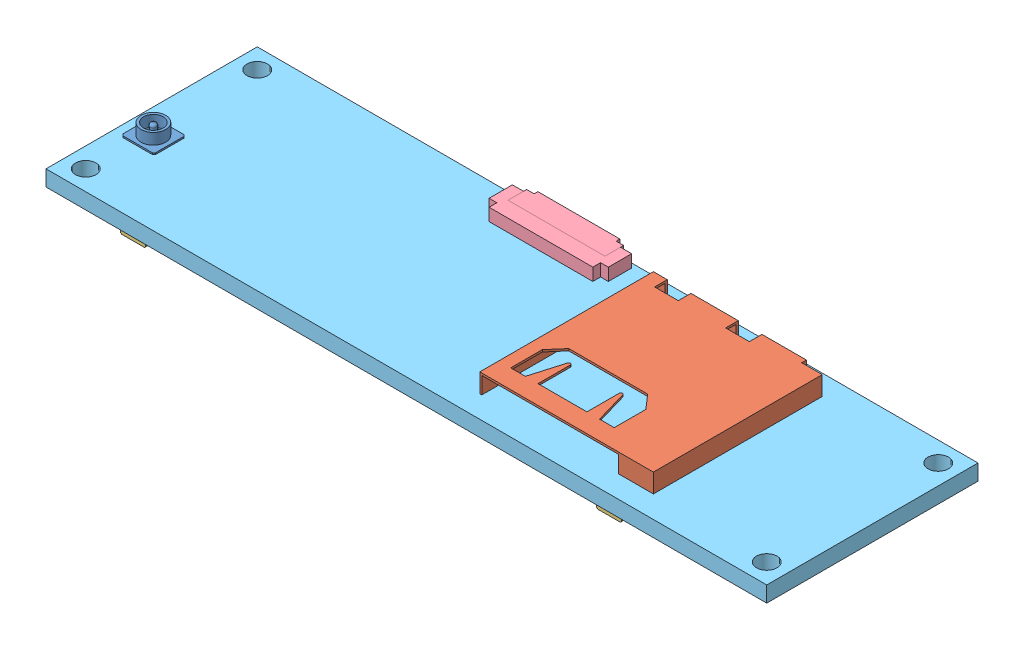
SolidWorks assembly OveroEarth-Water, configuration Default. Lengths in mm.
Overall size (58 3.99 17.2).
6 component instances, 5 part files, 0 mates.
Components (placement in the parent):
- u.FLCon-1: u.FLCon [Default] at (-26.9 0.762 1.96) size (2.63 1.02 2.54)
- MSDslot-1: MSDslot [Default] at (11.114 0.635 -0.263) size (13.97 1.52 13.97)
- AVX5602-70pinmale-1: AVX5602-70pinmale [Default] at (15.35 -0.635 0) x (-1 0 0) z (0 0 1) size (2 1.2 15.1)
- FH26-27S-1: FH26-27S [Default] at (-3.32 0.635 -6.9) x (-1 0 0) z (0 0 -1) size (9.6 1 3.05)
- overoEarth-Water-MOTHERBOARD-1: overoEarth-Water-MOTHERBOARD [Default] at origin size (58 1.27 17)
- AVX5602-70pinmale-2: AVX5602-70pinmale [Default] at (-22.95 -0.635 0) x (-1 0 0) z (0 0 1) size (2 1.2 15.1)
